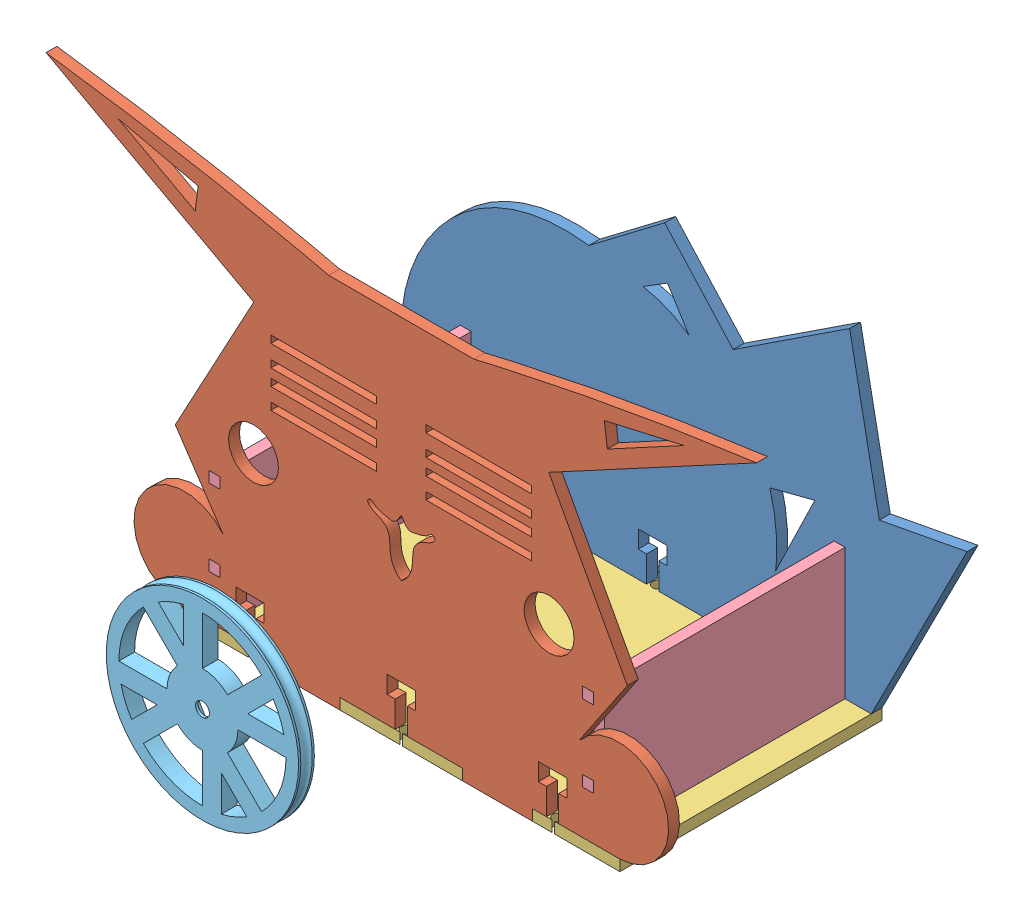
SolidWorks assembly PK_Assembly, configuration Default. Lengths in mm.
Overall size (206.41 173.35 117.79).
7 component instances, 5 part files, 12 mates.
Components (placement in the parent):
- PK_butt-1: PK_butt [Default] at (24.9347 68.0295 97.9634) size (167.03 96.98 3.17)
- PK01-1: PK01 [Default] at (66.8406 122.3115 172.5759) size (206.41 122.7 3.17)
- PK_base-1: PK_base [Default] at (65.8352 59.9585 137.6509) size (127 3.17 76.2)
- Front_Side-1: Front_Side [Default] at (9.9552 82.1835 137.6509) x (0 0 -1) z (1 0 0) size (76.2 41.28 3.17)
- Front_Side-2: Front_Side [Default] at (118.5402 82.1835 137.6509) x (0 0 -1) z (1 0 0) size (76.2 41.28 3.17)
- Wheel-1: Wheel [Default] at (39.3918 71.4928 204.7822) x (0 1 0) z (1 0 0) size (55.88 4.57 55.88)
- Wheel-2: Wheel [Default] at (33.172 37.2531 91.5649) x (1 0 0) z (0 -1 0) size (55.88 4.57 55.88)
Mates (geometry in assembly coordinates):
- Coincident9: coincident aligned: plane of PK_butt-1 through (-1.1955 115.2686 99.5509) normal (0 0 -1); plane of PK_base-1 through (2.3352 63.1335 99.5509) normal (0 0 -1)
- Coincident10: coincident anti-aligned: plane of PK_butt-1 through (129.3352 63.1335 102.7259) normal (0 -1 0); plane of PK_base-1 through (65.8352 63.1335 137.6509) normal (0 1 0)
- Coincident13: coincident anti-aligned: plane of PK01-1 through (66.8406 63.1335 175.7509) normal (0 -1 0); plane of PK_base-1 through (65.8352 63.1335 137.6509) normal (0 1 0)
- Coincident15: coincident anti-aligned: plane of PK_base-1 through (65.8352 63.1335 137.6509) normal (0 1 0); plane of Front_Side-1 through (13.1302 63.1335 102.7259) normal (0 -1 0)
- Coincident16: coincident anti-aligned: plane of PK_butt-1 through (-1.1955 115.2686 102.7259) normal (0 0 1); plane of Front_Side-1 through (13.1302 101.2335 102.7259) normal (0 0 -1)
- Coincident17: coincident anti-aligned: plane of PK_base-1 through (65.8352 63.1335 137.6509) normal (0 1 0); plane of Front_Side-2 through (121.7152 63.1335 102.7259) normal (0 -1 0)
- Coincident18: coincident anti-aligned: plane of PK_butt-1 through (-1.1955 115.2686 102.7259) normal (0 0 1); plane of Front_Side-2 through (121.7152 101.2335 102.7259) normal (0 0 -1)
- Coincident19: coincident aligned: line of PK01-1 through (129.3352 63.1335 175.7509) axis (0 0 -1); line of PK_base-1 through (129.3352 63.1335 175.7509) axis (0 0 -1)
- Coincident20: coincident aligned: line of PK01-1 through (2.3352 63.1335 175.7509) axis (1 0 0); line of PK_base-1 through (2.3352 63.1335 175.7509) axis (1 0 0)
- Coincident21: coincident anti-aligned: line of PK_butt-1 through (2.3352 63.1335 102.7259) axis (0 0 -1); line of PK_base-1 through (2.3352 63.1335 99.5509) axis (0 0 1)
- Coincident23: coincident anti-aligned: plane of PK01-1 through (9.9552 75.8335 175.7509) normal (1 0 0); plane of Front_Side-1 through (9.9552 82.1835 137.6509) normal (-1 0 0)
- Coincident25: coincident anti-aligned: plane of PK01-1 through (118.5402 75.8335 175.7509) normal (1 0 0); plane of Front_Side-2 through (118.5402 82.1835 137.6509) normal (-1 0 0)
